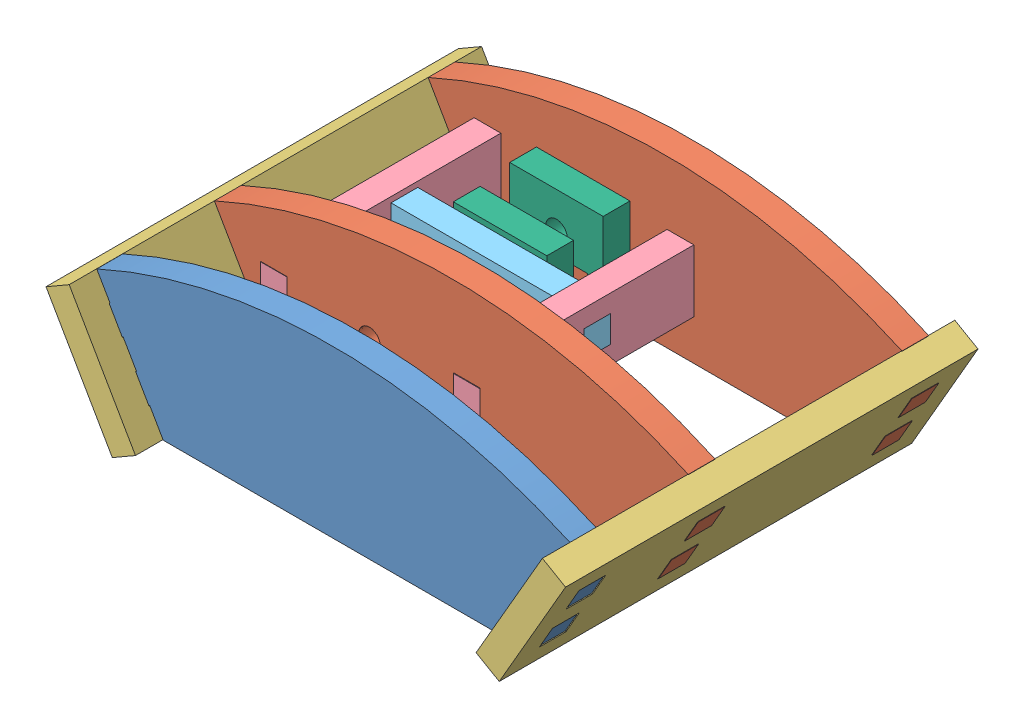
SolidWorks assembly newFootAssemblyForEndActuators, configuration Default. Lengths in mm.
Overall size (100.02 34.66 79.4).
10 component instances, 6 part files, 18 mates.
Components (placement in the parent):
- newFootWithTabs-1: newFootWithTabs [Default] at (38.6805 -18.084 117.5495) size (94.78 32.01 5)
- newFootWithTabsWithCutout-1: newFootWithTabsWithCutout [Default] at (38.8104 -18.009 53.5995) size (95.04 32.01 5.15)
- newFootConnector-3: newFootConnector [Default] at (5.9604 59.9777 127.8495) x (-0.5 0.866025 0) z (-0.866025 -0.5 0) size (25.53 79.4 5.15)
- newFootWithTabsWithCutout-2: newFootWithTabsWithCutout [Default] at (38.8104 -18.009 94.7495) size (95.04 32.01 5.15)
- connectorToMidPlateAndEndPlate - Copy-1: connectorToMidPlateAndEndPlate - Copy [Default] at (2.0504 67.7988 99.8995) x (0 0 -1) z (1 0 0) size (46.3 12 5.15)
- connectorToSpacerA-1: connectorToSpacerA [Default] at (2.0504 68.7503 74.7495) size (42.3 10 5.15)
- spacerA-1: spacerA [Default] at (14.0504 60.9184 58.7495) size (18 20 5.15)
- spacerA-2: spacerA [Default] at (14.0504 59.7803 69.5995) size (18 20 5.15)
- connectorToMidPlateAndEndPlate - Copy-2: connectorToMidPlateAndEndPlate - Copy [Default] at (39.2004 67.7503 99.8995) x (0 0 -1) z (1 0 0) size (46.3 12 5.15)
- newFootConnector-4: newFootConnector [Default] at (75.9905 57.3277 127.8495) x (0.5 0.866025 0) z (-0.866025 0.5 0) size (25.53 79.4 5.15)
Mates (geometry in assembly coordinates):
- Coincident44: coincident aligned: line of newFootWithTabs-1 through (-8.7117 75.0904 117.5495) axis (0.5 -0.866025 0); line of newFootConnector-3 through (-8.7117 75.0904 117.5495) axis (0.5 -0.866025 0)
- Coincident45: coincident aligned: line of newFootWithTabs-1 through (-8.7117 75.0904 122.5495) axis (0 0 -1); line of newFootConnector-3 through (-8.7117 75.0904 122.6995) axis (0 0 -1)
- Coincident50: coincident anti-aligned: line of connectorToSpacerA-1 through (44.3504 76.3253 79.8995) axis (0 0 -1); line of connectorToMidPlateAndEndPlate - Copy-2 through (44.3504 76.3253 74.7495) axis (0 0 1)
- Coincident51: coincident anti-aligned: line of connectorToSpacerA-1 through (44.3504 76.3253 79.8995) axis (0 0 -1); line of connectorToMidPlateAndEndPlate - Copy-2 through (44.3504 76.3253 74.7495) axis (0 0 1)
- Coincident52: coincident anti-aligned: line of connectorToSpacerA-1 through (44.3504 71.1753 79.8995) axis (0 1 0); line of connectorToMidPlateAndEndPlate - Copy-2 through (44.3504 76.3253 79.8995) axis (0 -1 0)
- Coincident55: coincident aligned: cylinder of connectorToSpacerA-1 through (23.0504 72.7503 74.7495) axis (0 0 1) radius 2.0675; circle of spacerA-2
- Coincident56: coincident anti-aligned: plane of connectorToSpacerA-1 through (2.0504 68.7503 74.7495) normal (0 0 -1); plane of spacerA-2 through (14.0504 59.7803 74.7495) normal (0 0 1)
- Coincident57: coincident aligned: line of newFootWithTabsWithCutout-1 through (-8.7117 75.0904 53.5995) axis (0.5 -0.866025 0); line of newFootConnector-3 through (-8.7117 75.0904 53.5995) axis (0.5 -0.866025 0)
- Coincident58: coincident anti-aligned: line of newFootWithTabsWithCutout-1 through (-6.1587 70.6684 58.7495) axis (0 0 -1); line of newFootConnector-3 through (-6.1587 70.6684 53.5995) axis (0 0 1)
- Coincident59: coincident aligned: line of newFootConnector-3 through (-8.7117 75.0904 94.7495) axis (0.5 -0.866025 0); line of newFootWithTabsWithCutout-2 through (-8.7117 75.0904 94.7495) axis (0.5 -0.866025 0)
- Coincident60: coincident aligned: line of newFootConnector-3 through (-8.7117 75.0904 99.8995) axis (0 0 -1); line of newFootWithTabsWithCutout-2 through (-8.7117 75.0904 99.8995) axis (0 0 -1)
- Lock1: lock: unknown of newFootWithTabsWithCutout-1; unknown of newFootConnector-3
- Coincident61: coincident aligned: line of newFootWithTabsWithCutout-2 through (2.0504 76.4488 99.8995) axis (0 -1 0); line of connectorToMidPlateAndEndPlate - Copy-1 through (2.0504 76.3738 99.8995) axis (0 -1 0)
- Coincident62: coincident aligned: line of newFootWithTabsWithCutout-2 through (39.2004 76.4488 99.8995) axis (0 -1 0); line of connectorToMidPlateAndEndPlate - Copy-2 through (39.2004 76.3253 99.8995) axis (0 -1 0)
- Concentric1: concentric aligned: cylinder of newFootWithTabsWithCutout-1 through (23.0504 73.8884 53.5995) axis (0 0 1) radius 2.0675; cylinder of spacerA-1 through (23.0504 73.8884 58.7495) axis (0 0 1) radius 2.0675
- Coincident63: coincident anti-aligned: plane of newFootWithTabsWithCutout-1 through (38.8104 -18.009 58.7495) normal (0 0 1); plane of spacerA-1 through (14.0504 60.9184 58.7495) normal (0 0 -1)
- Parallel1: parallel aligned: plane of spacerA-1 through (32.0504 80.9184 63.8995) normal (0 1 0); plane of spacerA-2 through (32.0504 79.7803 74.7495) normal (0 1 0)
- Coincident66: coincident aligned: line of connectorToSpacerA-1 through (7.2004 68.7503 74.7495) axis (1 0 0); line of spacerA-2 through (17.0504 68.7503 74.7495) axis (1 0 0)
